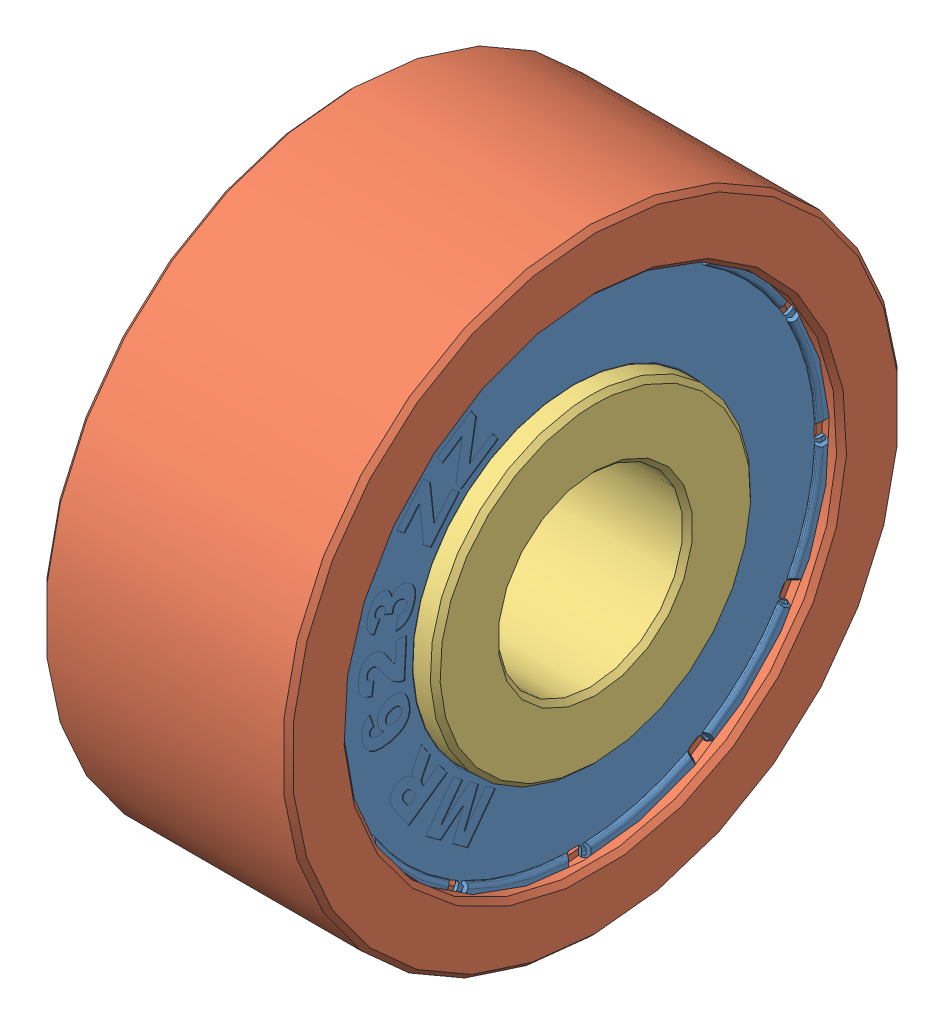
SolidWorks assembly Assem3, configuration Default. Lengths in mm.
Overall size (4 10 10).
4 component instances, 3 part files, 6 mates.
Components (placement in the parent):
- mr623zz-cen-1: mr623zz-cen [Default] at (0.5 0 0) size (0.23 8.2 8.2)
- mr623zz-ext-1: mr623zz-ext [Default] at origin size (4 10 10)
- mr623zz-int-1: mr623zz-int [Default] at origin size (4 5.2 5.2)
- mr623zz-cen-2: mr623zz-cen [Default] at (-0.5 0 0) x (-1 0 0) z (0 0 1) size (0.23 8.2 8.2)
Mates (geometry in assembly coordinates):
- Coincident2: coincident: point of ?
- Parallel1: parallel aligned: plane of mr623zz-int-1 through (2 -1.5 0) normal (1 0 0); plane of assembly through (0 0 0) normal (1 0 0)
- Coincident4: coincident anti-aligned: plane of mr623zz-cen-1 through (1.6 -2.65 0) normal (-1 0 0); plane of mr623zz-ext-1 through (1.6 -4 0) normal (1 0 0)
- Concentric1: concentric aligned: cylinder of mr623zz-cen-1 through (-5.929 0 0) axis (-1 0 0) radius 4.1; cylinder of mr623zz-ext-1 through (-6.429 0 0) axis (-1 0 0) radius 4.1
- Concentric2: concentric aligned: cylinder of mr623zz-ext-1 through (-6.429 0 0) axis (-1 0 0) radius 5; cylinder of mr623zz-int-1 through (-6.429 0 0) axis (-1 0 0) radius 1.5
- Coincident5: coincident aligned: plane of mr623zz-ext-1 through (2 -4 0) normal (1 0 0); plane of mr623zz-int-1 through (2 -1.5 0) normal (1 0 0)
